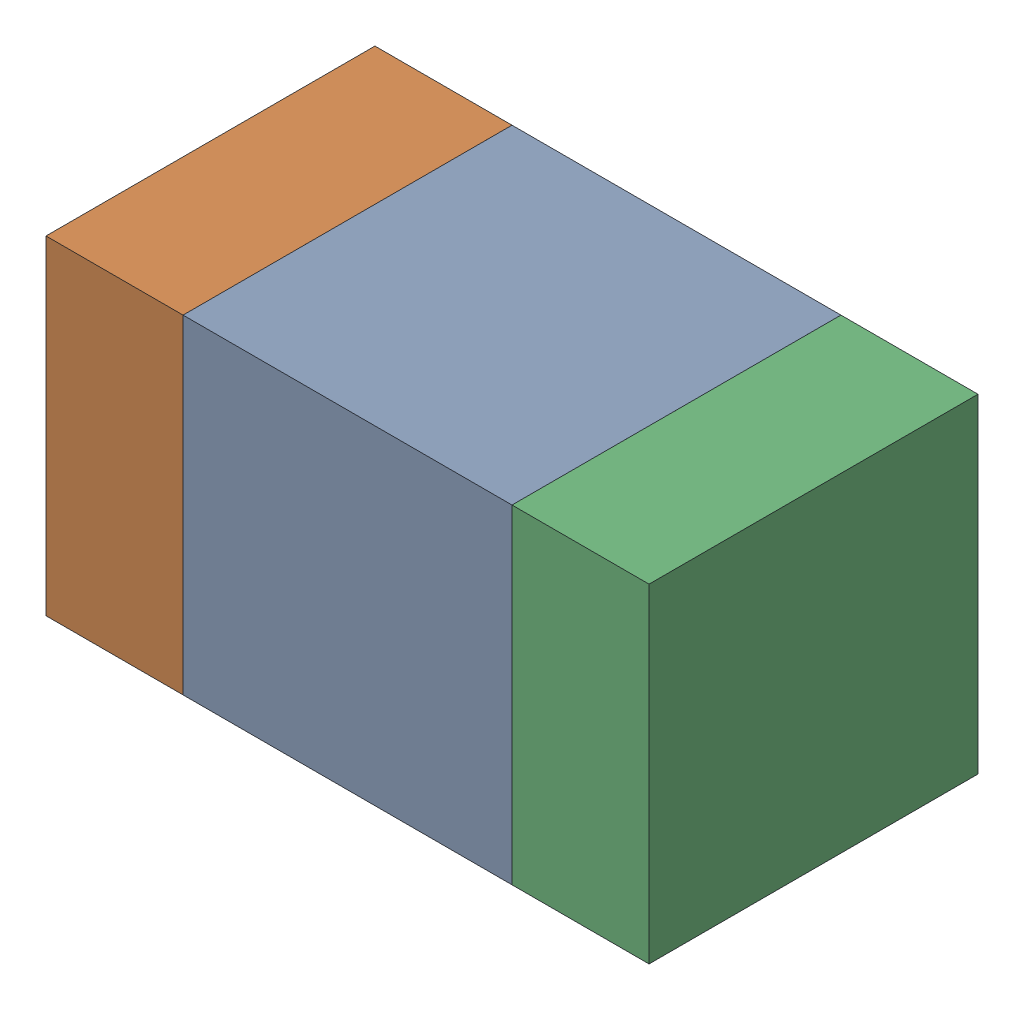
SolidWorks assembly C321_2PCB, configuration Default. Lengths in mm.
Overall size (1.1 0.6 0.6).
6 component instances, 2 part files, 0 mates.
Components (placement in the parent):
- 761606048-1: 761606048 [Default] at (132.9 87.9 -2.2638) size (0.6 0.6 0.6)
  - Extruded_9-1: Extruded_9 [Default] at origin size (0.6 0.6 0.6)
- 854785160-1: 854785160 [Default] at (132.475 87.9 -2.2638) size (0.25 0.6 0.6)
  - Extruded_19-1: Extruded_19 [Default] at origin size (0.25 0.6 0.6)
- 854785160-2: 854785160 [Default] at (133.325 87.9 -2.2638) size (0.25 0.6 0.6)
  - Extruded_19-1: Extruded_19 [Default] at origin size (0.25 0.6 0.6)
